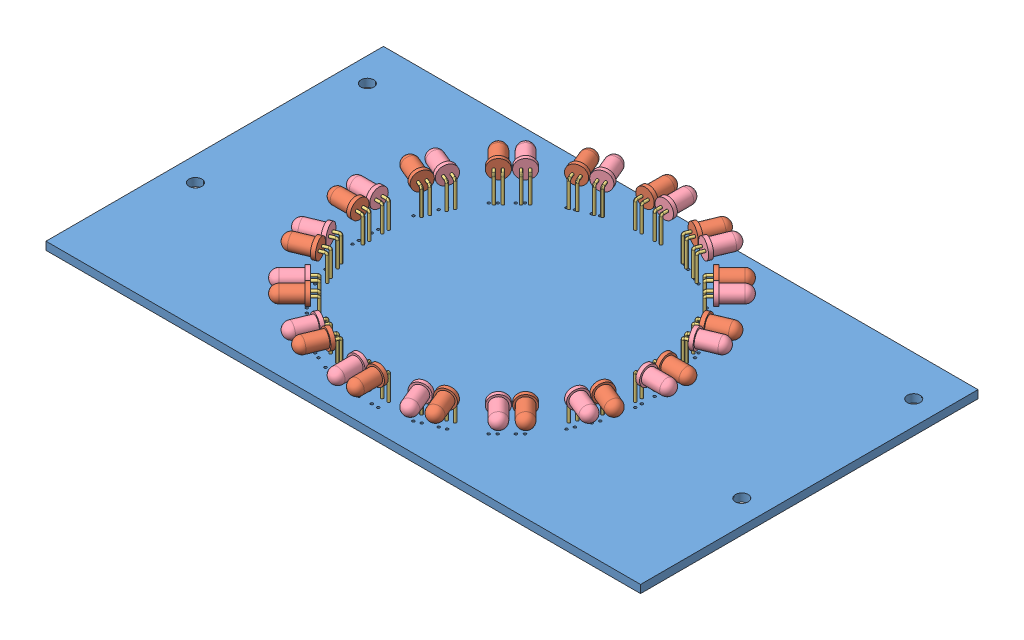
SolidWorks assembly BOM Ring, configuration Default. Lengths in mm.
Overall size (117.47 8.49 68.02).
129 component instances, 4 part files, 6 mates.
Components (placement in the parent):
- BOM board-1: BOM board [Default] at (-38.7289 1.1188 -4.2211) size (117.47 1.57 66.67)
- Black LED-4: Black LED [Default] at (-15.4454 6.9758 -21.6111) x (0 0 1) z (-1 0 0) size (7.36 6.92 3.66)
  - black LED-1: black LED [Default] at (34.3453 0.8052 12.8117) size (5.83 3.66 3.66)
  - led lead-1: led lead [Default] at (-0.1543 0.7979 1.7074) x (0 1 0) z (-1 0 0) size (5.34 0.52 1.53)
  - led lead-2: led lead [Default] at (-0.1543 0.7979 0.4374) x (0 1 0) z (-1 0 0) size (5.34 0.52 1.53)
- White LED-2: White LED [Default] at (-11.6354 6.9758 -21.6111) x (0 0 1) z (-1 0 0) size (7.36 6.92 3.66)
  - purple LED-1: purple LED [Default] at (34.3453 0.8052 12.8117) size (5.83 3.66 3.66)
  - led lead-1: led lead [Default] at (-0.1543 0.7979 1.7074) x (0 1 0) z (-1 0 0) size (5.34 0.52 1.53)
  - led lead-2: led lead [Default] at (-0.1543 0.7979 0.4374) x (0 1 0) z (-1 0 0) size (5.34 0.52 1.53)
- Black LED-17: Black LED [Default] at (-26.1074 6.9758 -19.159) x (0.382683 0 0.92388) z (-0.92388 0 0.382683) size (7.36 6.92 3.66)
  - black LED-1: black LED [Default] at (34.3453 0.8052 12.8117) size (5.83 3.66 3.66)
  - led lead-1: led lead [Default] at (-0.1543 0.7979 1.7074) x (0 1 0) z (-1 0 0) size (5.34 0.52 1.53)
  - led lead-2: led lead [Default] at (-0.1543 0.7979 0.4374) x (0 1 0) z (-1 0 0) size (5.34 0.52 1.53)
- Black LED-18: Black LED [Default] at (-35.0196 6.9758 -12.8134) x (0.707107 0 0.707107) z (-0.707107 0 0.707107) size (7.36 6.92 3.66)
  - black LED-1: black LED [Default] at (34.3453 0.8052 12.8117) size (5.83 3.66 3.66)
  - led lead-1: led lead [Default] at (-0.1543 0.7979 1.7074) x (0 1 0) z (-1 0 0) size (5.34 0.52 1.53)
  - led lead-2: led lead [Default] at (-0.1543 0.7979 0.4374) x (0 1 0) z (-1 0 0) size (5.34 0.52 1.53)
- Black LED-19: Black LED [Default] at (-40.8249 6.9758 -3.5403) x (0.92388 0 0.382683) z (-0.382683 0 0.92388) size (7.36 6.92 3.66)
  - black LED-1: black LED [Default] at (34.3453 0.8052 12.8117) size (5.83 3.66 3.66)
  - led lead-1: led lead [Default] at (-0.1543 0.7979 1.7074) x (0 1 0) z (-1 0 0) size (5.34 0.52 1.53)
  - led lead-2: led lead [Default] at (-0.1543 0.7979 0.4374) x (0 1 0) z (-1 0 0) size (5.34 0.52 1.53)
- Black LED-20: Black LED [Default] at (-42.6397 6.9758 7.2485) size (7.36 6.92 3.66)
  - black LED-1: black LED [Default] at (34.3453 0.8052 12.8117) size (5.83 3.66 3.66)
  - led lead-1: led lead [Default] at (-0.1543 0.7979 1.7074) x (0 1 0) z (-1 0 0) size (5.34 0.52 1.53)
  - led lead-2: led lead [Default] at (-0.1543 0.7979 0.4374) x (0 1 0) z (-1 0 0) size (5.34 0.52 1.53)
- Black LED-21: Black LED [Default] at (-40.1877 6.9758 17.9106) x (0.92388 0 -0.382683) z (0.382683 0 0.92388) size (7.36 6.92 3.66)
  - black LED-1: black LED [Default] at (34.3453 0.8052 12.8117) size (5.83 3.66 3.66)
  - led lead-1: led lead [Default] at (-0.1543 0.7979 1.7074) x (0 1 0) z (-1 0 0) size (5.34 0.52 1.53)
  - led lead-2: led lead [Default] at (-0.1543 0.7979 0.4374) x (0 1 0) z (-1 0 0) size (5.34 0.52 1.53)
- Black LED-22: Black LED [Default] at (-33.8421 6.9758 26.8227) x (0.707107 0 -0.707107) z (0.707107 0 0.707107) size (7.36 6.92 3.66)
  - black LED-1: black LED [Default] at (34.3453 0.8052 12.8117) size (5.83 3.66 3.66)
  - led lead-1: led lead [Default] at (-0.1543 0.7979 1.7074) x (0 1 0) z (-1 0 0) size (5.34 0.52 1.53)
  - led lead-2: led lead [Default] at (-0.1543 0.7979 0.4374) x (0 1 0) z (-1 0 0) size (5.34 0.52 1.53)
- Black LED-23: Black LED [Default] at (-24.569 6.9758 32.6281) x (0.382683 0 -0.92388) z (0.92388 0 0.382683) size (7.36 6.92 3.66)
  - black LED-1: black LED [Default] at (34.3453 0.8052 12.8117) size (5.83 3.66 3.66)
  - led lead-1: led lead [Default] at (-0.1543 0.7979 1.7074) x (0 1 0) z (-1 0 0) size (5.34 0.52 1.53)
  - led lead-2: led lead [Default] at (-0.1543 0.7979 0.4374) x (0 1 0) z (-1 0 0) size (5.34 0.52 1.53)
- Black LED-24: Black LED [Default] at (-13.7802 6.9758 34.4429) x (0 0 -1) z (1 0 0) size (7.36 6.92 3.66)
  - black LED-1: black LED [Default] at (34.3453 0.8052 12.8117) size (5.83 3.66 3.66)
  - led lead-1: led lead [Default] at (-0.1543 0.7979 1.7074) x (0 1 0) z (-1 0 0) size (5.34 0.52 1.53)
  - led lead-2: led lead [Default] at (-0.1543 0.7979 0.4374) x (0 1 0) z (-1 0 0) size (5.34 0.52 1.53)
- Black LED-25: Black LED [Default] at (-3.1181 6.9758 31.9908) x (-0.382683 0 -0.92388) z (0.92388 0 -0.382683) size (7.36 6.92 3.66)
  - black LED-1: black LED [Default] at (34.3453 0.8052 12.8117) size (5.83 3.66 3.66)
  - led lead-1: led lead [Default] at (-0.1543 0.7979 1.7074) x (0 1 0) z (-1 0 0) size (5.34 0.52 1.53)
  - led lead-2: led lead [Default] at (-0.1543 0.7979 0.4374) x (0 1 0) z (-1 0 0) size (5.34 0.52 1.53)
- Black LED-26: Black LED [Default] at (5.794 6.9758 25.6452) x (-0.707107 0 -0.707107) z (0.707107 0 -0.707107) size (7.36 6.92 3.66)
  - black LED-1: black LED [Default] at (34.3453 0.8052 12.8117) size (5.83 3.66 3.66)
  - led lead-1: led lead [Default] at (-0.1543 0.7979 1.7074) x (0 1 0) z (-1 0 0) size (5.34 0.52 1.53)
  - led lead-2: led lead [Default] at (-0.1543 0.7979 0.4374) x (0 1 0) z (-1 0 0) size (5.34 0.52 1.53)
- Black LED-27: Black LED [Default] at (11.5994 6.9758 16.3722) x (-0.92388 0 -0.382683) z (0.382683 0 -0.92388) size (7.36 6.92 3.66)
  - black LED-1: black LED [Default] at (34.3453 0.8052 12.8117) size (5.83 3.66 3.66)
  - led lead-1: led lead [Default] at (-0.1543 0.7979 1.7074) x (0 1 0) z (-1 0 0) size (5.34 0.52 1.53)
  - led lead-2: led lead [Default] at (-0.1543 0.7979 0.4374) x (0 1 0) z (-1 0 0) size (5.34 0.52 1.53)
- Black LED-28: Black LED [Default] at (13.4142 6.9758 5.5833) x (-1 0 0) z (0 0 -1) size (7.36 6.92 3.66)
  - black LED-1: black LED [Default] at (34.3453 0.8052 12.8117) size (5.83 3.66 3.66)
  - led lead-1: led lead [Default] at (-0.1543 0.7979 1.7074) x (0 1 0) z (-1 0 0) size (5.34 0.52 1.53)
  - led lead-2: led lead [Default] at (-0.1543 0.7979 0.4374) x (0 1 0) z (-1 0 0) size (5.34 0.52 1.53)
- Black LED-29: Black LED [Default] at (10.9621 6.9758 -5.0787) x (-0.92388 0 0.382683) z (-0.382683 0 -0.92388) size (7.36 6.92 3.66)
  - black LED-1: black LED [Default] at (34.3453 0.8052 12.8117) size (5.83 3.66 3.66)
  - led lead-1: led lead [Default] at (-0.1543 0.7979 1.7074) x (0 1 0) z (-1 0 0) size (5.34 0.52 1.53)
  - led lead-2: led lead [Default] at (-0.1543 0.7979 0.4374) x (0 1 0) z (-1 0 0) size (5.34 0.52 1.53)
- Black LED-30: Black LED [Default] at (4.6166 6.9758 -13.9909) x (-0.707107 0 0.707107) z (-0.707107 0 -0.707107) size (7.36 6.92 3.66)
  - black LED-1: black LED [Default] at (34.3453 0.8052 12.8117) size (5.83 3.66 3.66)
  - led lead-1: led lead [Default] at (-0.1543 0.7979 1.7074) x (0 1 0) z (-1 0 0) size (5.34 0.52 1.53)
  - led lead-2: led lead [Default] at (-0.1543 0.7979 0.4374) x (0 1 0) z (-1 0 0) size (5.34 0.52 1.53)
- Black LED-31: Black LED [Default] at (-4.6565 6.9758 -19.7962) x (-0.382683 0 0.92388) z (-0.92388 0 -0.382683) size (7.36 6.92 3.66)
  - black LED-1: black LED [Default] at (34.3453 0.8052 12.8117) size (5.83 3.66 3.66)
  - led lead-1: led lead [Default] at (-0.1543 0.7979 1.7074) x (0 1 0) z (-1 0 0) size (5.34 0.52 1.53)
  - led lead-2: led lead [Default] at (-0.1543 0.7979 0.4374) x (0 1 0) z (-1 0 0) size (5.34 0.52 1.53)
- White LED-7: White LED [Default] at (-22.5875 6.9758 -20.617) x (0.382683 0 0.92388) z (-0.92388 0 0.382683) size (7.36 6.92 3.66)
  - purple LED-1: purple LED [Default] at (34.3453 0.8052 12.8117) size (5.83 3.66 3.66)
  - led lead-1: led lead [Default] at (-0.1543 0.7979 1.7074) x (0 1 0) z (-1 0 0) size (5.34 0.52 1.53)
  - led lead-2: led lead [Default] at (-0.1543 0.7979 0.4374) x (0 1 0) z (-1 0 0) size (5.34 0.52 1.53)
- White LED-8: White LED [Default] at (-32.3255 6.9758 -15.5075) x (0.707107 0 0.707107) z (-0.707107 0 0.707107) size (7.36 6.92 3.66)
  - purple LED-1: purple LED [Default] at (34.3453 0.8052 12.8117) size (5.83 3.66 3.66)
  - led lead-1: led lead [Default] at (-0.1543 0.7979 1.7074) x (0 1 0) z (-1 0 0) size (5.34 0.52 1.53)
  - led lead-2: led lead [Default] at (-0.1543 0.7979 0.4374) x (0 1 0) z (-1 0 0) size (5.34 0.52 1.53)
- White LED-9: White LED [Default] at (-39.3669 6.9758 -7.0603) x (0.92388 0 0.382683) z (-0.382683 0 0.92388) size (7.36 6.92 3.66)
  - purple LED-1: purple LED [Default] at (34.3453 0.8052 12.8117) size (5.83 3.66 3.66)
  - led lead-1: led lead [Default] at (-0.1543 0.7979 1.7074) x (0 1 0) z (-1 0 0) size (5.34 0.52 1.53)
  - led lead-2: led lead [Default] at (-0.1543 0.7979 0.4374) x (0 1 0) z (-1 0 0) size (5.34 0.52 1.53)
- White LED-10: White LED [Default] at (-42.6397 6.9758 3.4385) size (7.36 6.92 3.66)
  - purple LED-1: purple LED [Default] at (34.3453 0.8052 12.8117) size (5.83 3.66 3.66)
  - led lead-1: led lead [Default] at (-0.1543 0.7979 1.7074) x (0 1 0) z (-1 0 0) size (5.34 0.52 1.53)
  - led lead-2: led lead [Default] at (-0.1543 0.7979 0.4374) x (0 1 0) z (-1 0 0) size (5.34 0.52 1.53)
- White LED-11: White LED [Default] at (-41.6457 6.9758 14.3906) x (0.92388 0 -0.382683) z (0.382683 0 0.92388) size (7.36 6.92 3.66)
  - purple LED-1: purple LED [Default] at (34.3453 0.8052 12.8117) size (5.83 3.66 3.66)
  - led lead-1: led lead [Default] at (-0.1543 0.7979 1.7074) x (0 1 0) z (-1 0 0) size (5.34 0.52 1.53)
  - led lead-2: led lead [Default] at (-0.1543 0.7979 0.4374) x (0 1 0) z (-1 0 0) size (5.34 0.52 1.53)
- White LED-12: White LED [Default] at (-36.5362 6.9758 24.1286) x (0.707107 0 -0.707107) z (0.707107 0 0.707107) size (7.36 6.92 3.66)
  - purple LED-1: purple LED [Default] at (34.3453 0.8052 12.8117) size (5.83 3.66 3.66)
  - led lead-1: led lead [Default] at (-0.1543 0.7979 1.7074) x (0 1 0) z (-1 0 0) size (5.34 0.52 1.53)
  - led lead-2: led lead [Default] at (-0.1543 0.7979 0.4374) x (0 1 0) z (-1 0 0) size (5.34 0.52 1.53)
- White LED-13: White LED [Default] at (-28.089 6.9758 31.17) x (0.382683 0 -0.92388) z (0.92388 0 0.382683) size (7.36 6.92 3.66)
  - purple LED-1: purple LED [Default] at (34.3453 0.8052 12.8117) size (5.83 3.66 3.66)
  - led lead-1: led lead [Default] at (-0.1543 0.7979 1.7074) x (0 1 0) z (-1 0 0) size (5.34 0.52 1.53)
  - led lead-2: led lead [Default] at (-0.1543 0.7979 0.4374) x (0 1 0) z (-1 0 0) size (5.34 0.52 1.53)
- White LED-14: White LED [Default] at (-17.5902 6.9758 34.4429) x (0 0 -1) z (1 0 0) size (7.36 6.92 3.66)
  - purple LED-1: purple LED [Default] at (34.3453 0.8052 12.8117) size (5.83 3.66 3.66)
  - led lead-1: led lead [Default] at (-0.1543 0.7979 1.7074) x (0 1 0) z (-1 0 0) size (5.34 0.52 1.53)
  - led lead-2: led lead [Default] at (-0.1543 0.7979 0.4374) x (0 1 0) z (-1 0 0) size (5.34 0.52 1.53)
- White LED-15: White LED [Default] at (-6.6381 6.9758 33.4489) x (-0.382683 0 -0.92388) z (0.92388 0 -0.382683) size (7.36 6.92 3.66)
  - purple LED-1: purple LED [Default] at (34.3453 0.8052 12.8117) size (5.83 3.66 3.66)
  - led lead-1: led lead [Default] at (-0.1543 0.7979 1.7074) x (0 1 0) z (-1 0 0) size (5.34 0.52 1.53)
  - led lead-2: led lead [Default] at (-0.1543 0.7979 0.4374) x (0 1 0) z (-1 0 0) size (5.34 0.52 1.53)
- White LED-16: White LED [Default] at (3.0999 6.9758 28.3393) x (-0.707107 0 -0.707107) z (0.707107 0 -0.707107) size (7.36 6.92 3.66)
  - purple LED-1: purple LED [Default] at (34.3453 0.8052 12.8117) size (5.83 3.66 3.66)
  - led lead-1: led lead [Default] at (-0.1543 0.7979 1.7074) x (0 1 0) z (-1 0 0) size (5.34 0.52 1.53)
  - led lead-2: led lead [Default] at (-0.1543 0.7979 0.4374) x (0 1 0) z (-1 0 0) size (5.34 0.52 1.53)
- White LED-17: White LED [Default] at (10.1413 6.9758 19.8921) x (-0.92388 0 -0.382683) z (0.382683 0 -0.92388) size (7.36 6.92 3.66)
  - purple LED-1: purple LED [Default] at (34.3453 0.8052 12.8117) size (5.83 3.66 3.66)
  - led lead-1: led lead [Default] at (-0.1543 0.7979 1.7074) x (0 1 0) z (-1 0 0) size (5.34 0.52 1.53)
  - led lead-2: led lead [Default] at (-0.1543 0.7979 0.4374) x (0 1 0) z (-1 0 0) size (5.34 0.52 1.53)
- White LED-18: White LED [Default] at (13.4142 6.9758 9.3933) x (-1 0 0) z (0 0 -1) size (7.36 6.92 3.66)
  - purple LED-1: purple LED [Default] at (34.3453 0.8052 12.8117) size (5.83 3.66 3.66)
  - led lead-1: led lead [Default] at (-0.1543 0.7979 1.7074) x (0 1 0) z (-1 0 0) size (5.34 0.52 1.53)
  - led lead-2: led lead [Default] at (-0.1543 0.7979 0.4374) x (0 1 0) z (-1 0 0) size (5.34 0.52 1.53)
- White LED-19: White LED [Default] at (12.4202 6.9758 -1.5588) x (-0.92388 0 0.382683) z (-0.382683 0 -0.92388) size (7.36 6.92 3.66)
  - purple LED-1: purple LED [Default] at (34.3453 0.8052 12.8117) size (5.83 3.66 3.66)
  - led lead-1: led lead [Default] at (-0.1543 0.7979 1.7074) x (0 1 0) z (-1 0 0) size (5.34 0.52 1.53)
  - led lead-2: led lead [Default] at (-0.1543 0.7979 0.4374) x (0 1 0) z (-1 0 0) size (5.34 0.52 1.53)
- White LED-20: White LED [Default] at (7.3106 6.9758 -11.2968) x (-0.707107 0 0.707107) z (-0.707107 0 -0.707107) size (7.36 6.92 3.66)
  - purple LED-1: purple LED [Default] at (34.3453 0.8052 12.8117) size (5.83 3.66 3.66)
  - led lead-1: led lead [Default] at (-0.1543 0.7979 1.7074) x (0 1 0) z (-1 0 0) size (5.34 0.52 1.53)
  - led lead-2: led lead [Default] at (-0.1543 0.7979 0.4374) x (0 1 0) z (-1 0 0) size (5.34 0.52 1.53)
- White LED-21: White LED [Default] at (-1.1365 6.9758 -18.3382) x (-0.382683 0 0.92388) z (-0.92388 0 -0.382683) size (7.36 6.92 3.66)
  - purple LED-1: purple LED [Default] at (34.3453 0.8052 12.8117) size (5.83 3.66 3.66)
  - led lead-1: led lead [Default] at (-0.1543 0.7979 1.7074) x (0 1 0) z (-1 0 0) size (5.34 0.52 1.53)
  - led lead-2: led lead [Default] at (-0.1543 0.7979 0.4374) x (0 1 0) z (-1 0 0) size (5.34 0.52 1.53)
Mates (geometry in assembly coordinates):
- Concentric13: concentric anti-aligned: cylinder of BOM board-1; cylinder of Black LED-4/led lead-1
- Concentric14: concentric anti-aligned: cylinder of BOM board-1; cylinder of Black LED-4/led lead-2
- Concentric21: concentric anti-aligned: cylinder of BOM board-1; cylinder of White LED-2/led lead-1
- Concentric22: concentric anti-aligned: cylinder of BOM board-1; cylinder of White LED-2/led lead-2
- Coincident10: coincident aligned: plane of Black LED-4/led lead-2 through (-16.1398 2.6936 -20.7524) normal (0 -1 0); plane of White LED-2/led lead-2 through (-12.3298 2.6936 -20.7524) normal (0 -1 0)
- Coincident11: coincident anti-aligned: unknown of BOM board-1; unknown of White LED-2/led lead-2
